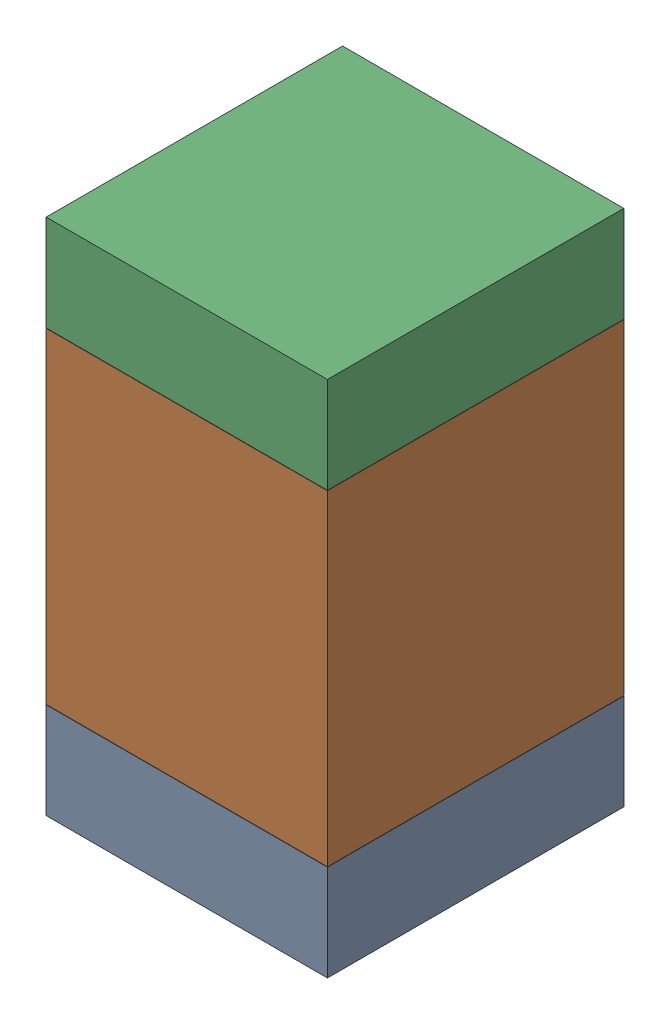
SolidWorks assembly R24, configuration Default. Lengths in mm.
Overall size (0.95 1.75 1).
6 component instances, 2 part files, 0 mates.
Components (placement in the parent):
- 6575495072-1: 6575495072 [Default] at (1.651 4.7485 0) size (0.95 0.32 1)
  - Extruded_6-1: Extruded_6 [Default] at origin size (0.95 0.32 1)
- 6575494912-1: 6575494912 [Default] at (1.651 5.461 0) size (0.95 1.1 1)
  - Extruded_7-1: Extruded_7 [Default] at origin size (0.95 1.1 1)
- 6575495072-2: 6575495072 [Default] at (1.651 6.1735 0) size (0.95 0.32 1)
  - Extruded_6-1: Extruded_6 [Default] at origin size (0.95 0.32 1)
